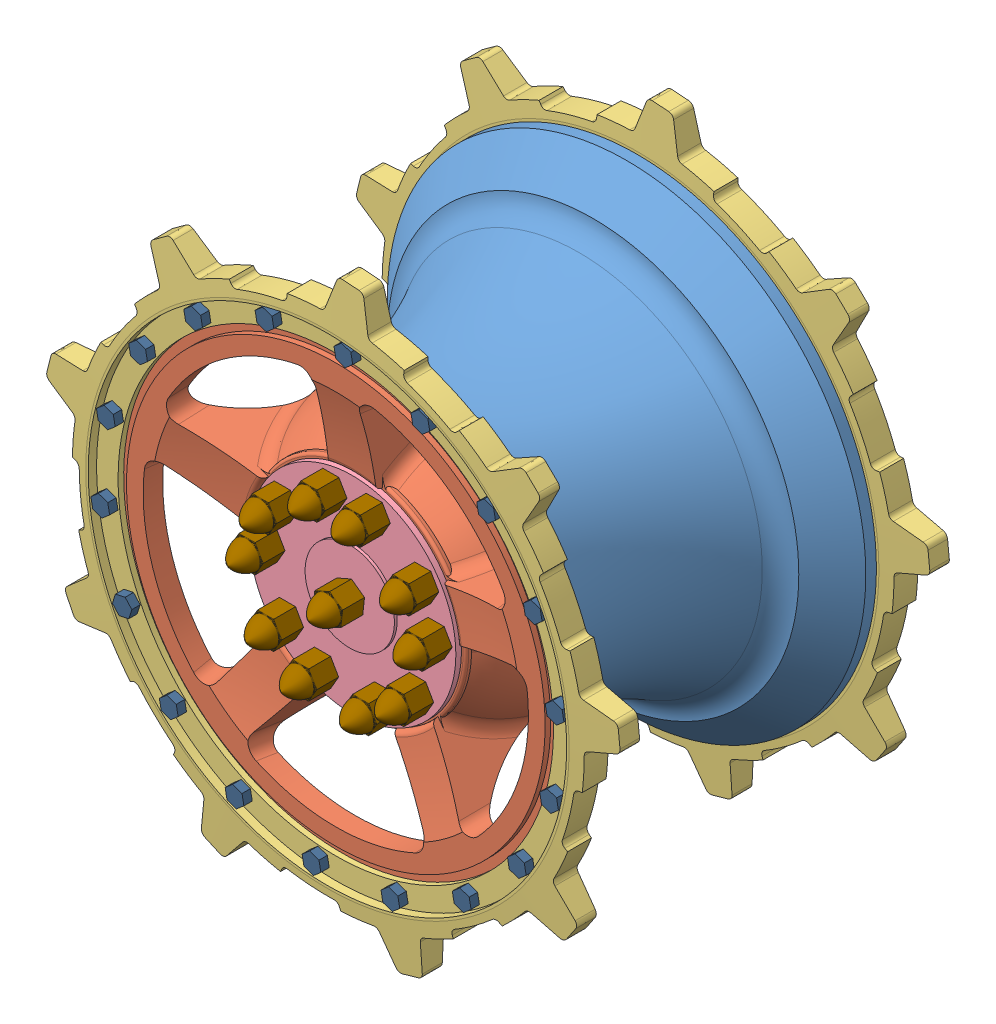
SolidWorks assembly Drive Wheel, configuration Default. Lengths in mm.
Overall size (36.71 36.7 16.14).
94 component instances, 10 part files, 114 mates.
Components (placement in the parent):
- Drive Wheel inner hub-1: Drive Wheel inner hub [Default] at (9.6783 0.3755 -10.4549) size (21.77 21.77 10.19)
- Drive Wheel outer hub-1: Drive Wheel outer hub [Default] at (9.6783 0.3755 3.5405) x (-0.809017 -0.587785 0) z (0 0 -1) size (21.77 21.77 4.19)
- Drive Wheel Sprocket-1: Drive Wheel Sprocket [Default] at (9.6783 0.3755 3.5913) x (0.997564 -0.069756 0) z (0 0 1) size (26.15 25.76 1.17)
- Drive Wheel Sprocket-2: Drive Wheel Sprocket [Default] at (9.6783 0.3755 -10.5057) x (-0.71934 0.694658 0) z (0 0 -1) size (26.15 25.76 1.17)
- Drive Wheel Bearing Plate-1: Drive Wheel Bearing Plate [Default] at (6.2039 -0.1061 2.7785) size (9.4 9.4 0.38)
- Drive Wheel Bearing Assembly-1: Drive Wheel Bearing Assembly [Default] at (10.4373 0.6578 -3.4809) x (1 0 0) z (0 1 0) size (5.14 1.27 5.06)
  - Drive Wheel Bearing-1: Drive Wheel Bearing [Default] at (-0.759 1.0051 -0.2823) size (4.83 1.27 4.83)
  - Drive Wheel Bearing Roller-1: Drive Wheel Bearing Roller [Default] at (-0.759 -0.1093 1.8348) x (-0.999426 -0.00354 0.033681) z (0 0.994522 0.104528) size (0.64 0.64 0.89)
  - Drive Wheel Bearing Roller-2: Drive Wheel Bearing Roller [Default] at (-2.6729 0.7749 -1.3873) x (0.789274 0.103648 0.60523) z (0.090524 -0.994522 0.052264) size (0.64 0.64 0.89)
  - Drive Wheel Bearing Roller-3: Drive Wheel Bearing Roller [Default] at (-0.759 0.7749 -2.4923) x (1 0 0) z (0 -0.994522 0.104528) size (0.64 0.64 0.89)
  - Drive Wheel Bearing Roller-4: Drive Wheel Bearing Roller [Default] at (-0.0031 0.7749 -2.3591) x (0.927484 0.003582 0.373846) z (-0.035751 -0.994522 0.098225) size (0.64 0.64 0.89)
  - Drive Wheel Bearing Roller-5: Drive Wheel Bearing Roller [Default] at (-2.1199 -0.1093 1.3395) x (0.99582 0.061868 0.06719) z (-0.06719 0.994522 0.080073) size (0.64 0.64 0.89)
  - Drive Wheel Bearing Roller-6: Drive Wheel Bearing Roller [Default] at (-2.8439 -0.1093 0.0853) x (0.979533 0.098182 0.175711) z (-0.10294 0.994522 0.018151) size (0.64 0.64 0.89)
  - Drive Wheel Bearing Roller-7: Drive Wheel Bearing Roller [Default] at (-2.1796 0.7749 -1.9753) x (0.99582 0.061868 -0.06719) z (0.06719 -0.994522 0.080073) size (0.64 0.64 0.89)
  - Drive Wheel Bearing Roller-8: Drive Wheel Bearing Roller [Default] at (-2.5925 -0.1093 0.7762) x (0.992212 0.085557 0.090524) z (-0.090524 0.994522 0.052264) size (0.64 0.64 0.89)
  - Drive Wheel Bearing Roller-9: Drive Wheel Bearing Roller [Default] at (-1.4831 -0.1093 1.7071) x (0.998836 0.032375 0.035751) z (-0.035751 0.994522 0.098225) size (0.64 0.64 0.89)
  - Drive Wheel Bearing Roller-10: Drive Wheel Bearing Roller [Default] at (-1.5149 0.7749 -2.3591) x (0.998836 0.032375 -0.035751) z (0.035751 -0.994522 0.098225) size (0.64 0.64 0.89)
  - Drive Wheel Bearing Roller-11: Drive Wheel Bearing Roller [Default] at (-2.9355 0.7749 -0.6661) x (0.986505 0.104412 0.126122) z (0.10294 -0.994522 0.018151) size (0.64 0.64 0.89)
  - Drive Wheel Bearing Roller-12: Drive Wheel Bearing Roller [Default] at (1.4174 0.7749 -0.6661) x (0.885883 -0.083366 0.456356) z (-0.10294 -0.994522 0.018151) size (0.64 0.64 0.89)
  - Drive Wheel Bearing Roller-13: Drive Wheel Bearing Roller [Default] at (1.0745 -0.1093 0.7762) x (0.992212 -0.085557 -0.090524) z (0.090524 0.994522 0.052264) size (0.64 0.64 0.89)
  - Drive Wheel Bearing Roller-14: Drive Wheel Bearing Roller [Default] at (0.6018 -0.1093 1.3395) x (0.874291 -0.097355 0.47554) z (0.06719 0.994522 0.080073) size (0.64 0.64 0.89)
  - Drive Wheel Bearing Roller-15: Drive Wheel Bearing Roller [Default] at (0.6616 0.7749 -1.9753) x (0.913673 -0.093574 -0.395532) z (-0.06719 -0.994522 0.080073) size (0.64 0.64 0.89)
  - Drive Wheel Bearing Roller-16: Drive Wheel Bearing Roller [Default] at (1.1549 0.7749 -1.3873) x (0.899555 -0.059136 0.432785) z (-0.090524 -0.994522 0.052264) size (0.64 0.64 0.89)
  - Drive Wheel Bearing Roller-17: Drive Wheel Bearing Roller [Default] at (1.3259 -0.1093 0.0853) x (0.989592 -0.100551 -0.10294) z (0.10294 0.994522 0.018151) size (0.64 0.64 0.89)
  - Drive Wheel Bearing Roller-18: Drive Wheel Bearing Roller [Default] at (-0.0349 -0.1093 1.7071) x (0.70634 -0.094677 0.701512) z (0.035751 0.994522 0.098225) size (0.64 0.64 0.89)
- Drive Wheel Bearing Assembly-2: Drive Wheel Bearing Assembly [Default] at (9.7005 -0.434 0.5034) x (0.374215 -0.927342 0) z (-0.927342 -0.374215 0) size (5.14 1.27 5.06)
  - Drive Wheel Bearing-1: Drive Wheel Bearing [Default] at (-0.759 1.0051 -0.2823) size (4.83 1.27 4.83)
  - Drive Wheel Bearing Roller-1: Drive Wheel Bearing Roller [Default] at (-0.759 -0.1093 1.8348) x (-0.999426 -0.00354 0.033681) z (0 0.994522 0.104528) size (0.64 0.64 0.89)
  - Drive Wheel Bearing Roller-2: Drive Wheel Bearing Roller [Default] at (-2.6729 0.7749 -1.3873) x (0.789274 0.103648 0.60523) z (0.090524 -0.994522 0.052264) size (0.64 0.64 0.89)
  - Drive Wheel Bearing Roller-3: Drive Wheel Bearing Roller [Default] at (-0.759 0.7749 -2.4923) x (1 0 0) z (0 -0.994522 0.104528) size (0.64 0.64 0.89)
  - Drive Wheel Bearing Roller-4: Drive Wheel Bearing Roller [Default] at (-0.0031 0.7749 -2.3591) x (0.927484 0.003582 0.373846) z (-0.035751 -0.994522 0.098225) size (0.64 0.64 0.89)
  - Drive Wheel Bearing Roller-5: Drive Wheel Bearing Roller [Default] at (-2.1199 -0.1093 1.3395) x (0.99582 0.061868 0.06719) z (-0.06719 0.994522 0.080073) size (0.64 0.64 0.89)
  - Drive Wheel Bearing Roller-6: Drive Wheel Bearing Roller [Default] at (-2.8439 -0.1093 0.0853) x (0.979533 0.098182 0.175711) z (-0.10294 0.994522 0.018151) size (0.64 0.64 0.89)
  - Drive Wheel Bearing Roller-7: Drive Wheel Bearing Roller [Default] at (-2.1796 0.7749 -1.9753) x (0.99582 0.061868 -0.06719) z (0.06719 -0.994522 0.080073) size (0.64 0.64 0.89)
  - Drive Wheel Bearing Roller-8: Drive Wheel Bearing Roller [Default] at (-2.5925 -0.1093 0.7762) x (0.992212 0.085557 0.090524) z (-0.090524 0.994522 0.052264) size (0.64 0.64 0.89)
  - Drive Wheel Bearing Roller-9: Drive Wheel Bearing Roller [Default] at (-1.4831 -0.1093 1.7071) x (0.998836 0.032375 0.035751) z (-0.035751 0.994522 0.098225) size (0.64 0.64 0.89)
  - Drive Wheel Bearing Roller-10: Drive Wheel Bearing Roller [Default] at (-1.5149 0.7749 -2.3591) x (0.998836 0.032375 -0.035751) z (0.035751 -0.994522 0.098225) size (0.64 0.64 0.89)
  - Drive Wheel Bearing Roller-11: Drive Wheel Bearing Roller [Default] at (-2.9355 0.7749 -0.6661) x (0.986505 0.104412 0.126122) z (0.10294 -0.994522 0.018151) size (0.64 0.64 0.89)
  - Drive Wheel Bearing Roller-12: Drive Wheel Bearing Roller [Default] at (1.4174 0.7749 -0.6661) x (0.885883 -0.083366 0.456356) z (-0.10294 -0.994522 0.018151) size (0.64 0.64 0.89)
  - Drive Wheel Bearing Roller-13: Drive Wheel Bearing Roller [Default] at (1.0745 -0.1093 0.7762) x (0.992212 -0.085557 -0.090524) z (0.090524 0.994522 0.052264) size (0.64 0.64 0.89)
  - Drive Wheel Bearing Roller-14: Drive Wheel Bearing Roller [Default] at (0.6018 -0.1093 1.3395) x (0.874291 -0.097355 0.47554) z (0.06719 0.994522 0.080073) size (0.64 0.64 0.89)
  - Drive Wheel Bearing Roller-15: Drive Wheel Bearing Roller [Default] at (0.6616 0.7749 -1.9753) x (0.913673 -0.093574 -0.395532) z (-0.06719 -0.994522 0.080073) size (0.64 0.64 0.89)
  - Drive Wheel Bearing Roller-16: Drive Wheel Bearing Roller [Default] at (1.1549 0.7749 -1.3873) x (0.899555 -0.059136 0.432785) z (-0.090524 -0.994522 0.052264) size (0.64 0.64 0.89)
  - Drive Wheel Bearing Roller-17: Drive Wheel Bearing Roller [Default] at (1.3259 -0.1093 0.0853) x (0.989592 -0.100551 -0.10294) z (0.10294 0.994522 0.018151) size (0.64 0.64 0.89)
  - Drive Wheel Bearing Roller-18: Drive Wheel Bearing Roller [Default] at (-0.0349 -0.1093 1.7071) x (0.70634 -0.094677 0.701512) z (0.035751 0.994522 0.098225) size (0.64 0.64 0.89)
- Bearing Washer-1: Bearing Washer [Default] at (29.8938 -4.5317 1.7625) x (1 0 0) z (0 1 0) size (5.51 0.25 5.51)
- Bearing nut-1: Bearing nut [Default] at (9.6783 0.3755 2.5245) x (1 0 0) z (0 1 0) size (4.94 0.76 4.6)
- Drive Wheel Nut-1: Drive Wheel Nut [Default] at (11.0437 -3.1814 3.0325) size (1.47 1.31 7.99)
- Drive Wheel Nut-2: Drive Wheel Nut [Default] at (12.6392 -2.0222 3.0325) size (1.47 1.31 7.99)
- Drive Wheel Nut-3: Drive Wheel Nut [Default] at (13.4831 0.5749 3.0325) size (1.47 1.31 7.99)
- Drive Wheel Nut-4: Drive Wheel Nut [Default] at (12.8736 2.4506 3.0325) size (1.47 1.31 7.99)
- Drive Wheel Nut-5: Drive Wheel Nut [Default] at (6.7174 -2.0222 3.0325) size (1.47 1.31 7.99)
- Drive Wheel Nut-6: Drive Wheel Nut [Default] at (6.4829 2.4506 3.0325) size (1.47 1.31 7.99)
- Drive Wheel Nut-7: Drive Wheel Nut [Default] at (5.8735 0.5749 3.0325) size (1.47 1.31 7.99)
- Drive Wheel Nut-8: Drive Wheel Nut [Default] at (8.6922 4.0557 3.0325) size (1.47 1.31 7.99)
- Drive Wheel Nut-9: Drive Wheel Nut [Default] at (9.6783 0.3755 3.1595) x (0.107676 0.994186 0) z (0 0 1) size (1.47 1.31 7.99)
- Drive Wheel Nut-10: Drive Wheel Nut [Default] at (8.3129 -3.1814 3.0325) size (1.47 1.31 7.99)
- Drive Wheel Nut-11: Drive Wheel Nut [Default] at (10.6644 4.0557 3.0325) size (1.47 1.31 7.99)
- Sprocket bolt-1: Sprocket bolt [Default] at (10.4034 10.7452 3.1595) x (0.922387 0.386268 0) z (0.386268 -0.922387 0) size (0.86 1.02 0.88)
- Sprocket bolt-2: Sprocket bolt [Default] at (13.9063 9.8718 3.1595) x (0.922387 0.386268 0) z (0.386268 -0.922387 0) size (0.86 1.02 0.88)
- Sprocket bolt-3: Sprocket bolt [Default] at (16.8992 7.853 3.1595) x (0.922387 0.386268 0) z (0.386268 -0.922387 0) size (0.86 1.02 0.88)
- Sprocket bolt-4: Sprocket bolt [Default] at (19.0212 4.9324 3.1595) x (0.922387 0.386268 0) z (0.386268 -0.922387 0) size (0.86 1.02 0.88)
- Sprocket bolt-5: Sprocket bolt [Default] at (20.0163 1.4621 3.1595) x (0.922387 0.386268 0) z (0.386268 -0.922387 0) size (0.86 1.02 0.88)
- Sprocket bolt-6: Sprocket bolt [Default] at (19.7645 -2.1392 3.1595) x (0.922387 0.386268 0) z (0.386268 -0.922387 0) size (0.86 1.02 0.88)
- Sprocket bolt-7: Sprocket bolt [Default] at (18.2961 -5.4373 3.1595) x (0.922387 0.386268 0) z (0.386268 -0.922387 0) size (0.86 1.02 0.88)
- Sprocket bolt-8: Sprocket bolt [Default] at (15.7883 -8.0342 3.1595) x (0.922387 0.386268 0) z (0.386268 -0.922387 0) size (0.86 1.02 0.88)
- Sprocket bolt-9: Sprocket bolt [Default] at (12.5435 -9.6167 3.1595) x (0.922387 0.386268 0) z (0.386268 -0.922387 0) size (0.86 1.02 0.88)
- Sprocket bolt-10: Sprocket bolt [Default] at (8.9532 -9.9941 3.1595) x (0.922387 0.386268 0) z (0.386268 -0.922387 0) size (0.86 1.02 0.88)
- Sprocket bolt-11: Sprocket bolt [Default] at (5.4503 -9.1207 3.1595) x (0.922387 0.386268 0) z (0.386268 -0.922387 0) size (0.86 1.02 0.88)
- Sprocket bolt-12: Sprocket bolt [Default] at (2.4573 -7.102 3.1595) x (0.922387 0.386268 0) z (0.386268 -0.922387 0) size (0.86 1.02 0.88)
- Sprocket bolt-13: Sprocket bolt [Default] at (0.3354 -4.1813 3.1595) x (0.994954 -0.100336 0) z (-0.100336 -0.994954 0) size (0.86 1.02 0.88)
- Sprocket bolt-14: Sprocket bolt [Default] at (-0.6597 -0.711 3.1595) x (0.922387 0.386268 0) z (0.386268 -0.922387 0) size (0.86 1.02 0.88)
- Sprocket bolt-15: Sprocket bolt [Default] at (-0.4079 2.8903 3.1595) x (0.922387 0.386268 0) z (0.386268 -0.922387 0) size (0.86 1.02 0.88)
- Sprocket bolt-16: Sprocket bolt [Default] at (1.0605 6.1883 3.1595) x (0.922387 0.386268 0) z (0.386268 -0.922387 0) size (0.86 1.02 0.88)
- Sprocket bolt-17: Sprocket bolt [Default] at (3.5683 8.7852 3.1595) x (0.922387 0.386268 0) z (0.386268 -0.922387 0) size (0.86 1.02 0.88)
- Sprocket bolt-18: Sprocket bolt [Default] at (6.813 10.3678 3.1595) x (0.922387 0.386268 0) z (0.386268 -0.922387 0) size (0.86 1.02 0.88)
- Sprocket bolt-19: Sprocket bolt [Default] at (16.8992 7.853 -10.0739) x (0.782051 -0.623214 0) z (0.623214 0.782051 0) size (0.86 1.02 0.88)
- Sprocket bolt-20: Sprocket bolt [Default] at (13.9063 9.8718 -10.0739) x (0.998647 -0.052005 0) z (0.052005 0.998647 0) size (0.86 1.02 0.88)
- Sprocket bolt-21: Sprocket bolt [Default] at (10.4034 10.7452 -10.0739) x (0.998647 -0.052005 0) z (0.052005 0.998647 0) size (0.86 1.02 0.88)
- Sprocket bolt-22: Sprocket bolt [Default] at (6.813 10.3678 -10.0739) x (0.998647 -0.052005 0) z (0.052005 0.998647 0) size (0.86 1.02 0.88)
- Sprocket bolt-23: Sprocket bolt [Default] at (3.5683 8.7852 -10.0739) x (0.998647 -0.052005 0) z (0.052005 0.998647 0) size (0.86 1.02 0.88)
- Sprocket bolt-24: Sprocket bolt [Default] at (1.0605 6.1883 -10.0739) x (0.998647 -0.052005 0) z (0.052005 0.998647 0) size (0.86 1.02 0.88)
- Sprocket bolt-25: Sprocket bolt [Default] at (-0.4079 2.8903 -10.0739) x (0.998647 -0.052005 0) z (0.052005 0.998647 0) size (0.86 1.02 0.88)
- Sprocket bolt-26: Sprocket bolt [Default] at (-0.6597 -0.711 -10.0739) x (0.998647 -0.052005 0) z (0.052005 0.998647 0) size (0.86 1.02 0.88)
- Sprocket bolt-27: Sprocket bolt [Default] at (0.3354 -4.1813 -10.0739) x (0.998647 -0.052005 0) z (0.052005 0.998647 0) size (0.86 1.02 0.88)
- Sprocket bolt-28: Sprocket bolt [Default] at (2.4573 -7.102 -10.0739) x (0.998647 -0.052005 0) z (0.052005 0.998647 0) size (0.86 1.02 0.88)
- Sprocket bolt-29: Sprocket bolt [Default] at (5.4503 -9.1207 -10.0739) x (0.998647 -0.052005 0) z (0.052005 0.998647 0) size (0.86 1.02 0.88)
- Sprocket bolt-30: Sprocket bolt [Default] at (8.9532 -9.9941 -10.0739) x (0.998647 -0.052005 0) z (0.052005 0.998647 0) size (0.86 1.02 0.88)
- Sprocket bolt-31: Sprocket bolt [Default] at (12.5435 -9.6167 -10.0739) x (0.998647 -0.052005 0) z (0.052005 0.998647 0) size (0.86 1.02 0.88)
- Sprocket bolt-32: Sprocket bolt [Default] at (15.7883 -8.0342 -10.0739) x (0.998647 -0.052005 0) z (0.052005 0.998647 0) size (0.86 1.02 0.88)
- Sprocket bolt-33: Sprocket bolt [Default] at (18.2961 -5.4373 -10.0739) x (0.998647 -0.052005 0) z (0.052005 0.998647 0) size (0.86 1.02 0.88)
- Sprocket bolt-34: Sprocket bolt [Default] at (19.7645 -2.1392 -10.0739) x (0.998647 -0.052005 0) z (0.052005 0.998647 0) size (0.86 1.02 0.88)
- Sprocket bolt-35: Sprocket bolt [Default] at (20.0163 1.4621 -10.0739) x (0.998647 -0.052005 0) z (0.052005 0.998647 0) size (0.86 1.02 0.88)
- Sprocket bolt-36: Sprocket bolt [Default] at (19.0212 4.9324 -10.0739) x (0.998647 -0.052005 0) z (0.052005 0.998647 0) size (0.86 1.02 0.88)
Mates (geometry in assembly coordinates):
- Coincident1: coincident anti-aligned: plane of Drive Wheel inner hub-1 through (16.0384 0.3755 -0.2695) normal (0 0 1); plane of Drive Wheel outer hub-1 through (9.6783 0.3755 -0.2695) normal (0 0 -1)
- Concentric1: concentric aligned: cone of Drive Wheel inner hub-1 through (9.6783 0.3755 -4.4859) axis (0 0 1); cylinder of Drive Wheel outer hub-1 through (9.6783 0.3755 1.5085) axis (0 0 1) radius 3.0208
- Concentric2: concentric anti-aligned: cylinder of Drive Wheel inner hub-1 through (10.6644 4.0557 2.1181) axis (0 0 -1) radius 0.4445; cylinder of Drive Wheel outer hub-1 through (10.6644 4.0557 -0.3521) axis (0 0 1) radius 0.4445
- Coincident2: coincident anti-aligned: plane of Drive Wheel outer hub-1 through (9.6783 0.3755 3.5405) normal (0 0 1); plane of Drive Wheel Sprocket-1 through (9.6783 0.3755 3.5405) normal (0 0 -1)
- Concentric3: concentric anti-aligned: cylinder of Drive Wheel outer hub-1 through (9.6783 0.3755 2.9055) axis (0 0 1) radius 10.8839; cylinder of Drive Wheel Sprocket-1 through (9.6783 0.3755 4.1755) axis (0 0 -1) radius 10.8839
- Concentric4: concentric aligned: cylinder of Drive Wheel outer hub-1 through (10.4034 10.7452 3.1595) axis (0 0 1) radius 0.254; cylinder of Drive Wheel Sprocket-1 through (10.4034 10.7452 3.5405) axis (0 0 1) radius 0.254
- Coincident3: coincident anti-aligned: plane of Drive Wheel inner hub-1 through (9.6783 0.3755 -10.4549) normal (0 0 -1); plane of Drive Wheel Sprocket-2 through (9.6783 0.3755 -10.4549) normal (0 0 1)
- Concentric5: concentric anti-aligned: cylinder of Drive Wheel inner hub-1 through (9.6783 0.3755 -9.4389) axis (0 0 -1) radius 10.8839; cylinder of Drive Wheel Sprocket-2 through (9.6783 0.3755 -11.0899) axis (0 0 1) radius 10.8839
- Concentric6: concentric aligned: cylinder of Drive Wheel inner hub-1 through (10.4034 10.7452 -10.0739) axis (0 0 -1) radius 0.254; cylinder of Drive Wheel Sprocket-2 through (10.4034 10.7452 -10.4549) axis (0 0 -1) radius 0.254
- Concentric7: concentric aligned: cylinder of Drive Wheel outer hub-1 through (9.6783 0.3755 1.5085) axis (0 0 1) radius 3.0208; cylinder of Drive Wheel Bearing Assembly-2/Drive Wheel Bearing-1 through (9.6783 0.3755 0.2385) axis (0 0 1) radius 1.524
- Coincident4: coincident aligned: plane of Drive Wheel outer hub-1 through (9.6783 0.3755 1.5085) normal (0 0 1); plane of Drive Wheel Bearing Assembly-2/Drive Wheel Bearing-1 through (9.6783 0.3755 1.5085) normal (0 0 1)
- Coincident5: coincident anti-aligned: plane of Drive Wheel outer hub-1 through (9.6783 0.3755 1.5085) normal (0 0 1); plane of Bearing Washer-1 through (9.6783 0.3755 1.5085) normal (0 0 -1)
- Concentric8: concentric aligned: cylinder of Drive Wheel outer hub-1 through (9.6783 0.3755 1.5085) axis (0 0 1) radius 3.0208; cylinder of Bearing Washer-1 through (9.6783 0.3755 1.5085) axis (0 0 1) radius 1.524
- Coincident6: coincident anti-aligned: plane of Bearing Washer-1 through (9.6783 0.3755 1.7625) normal (0 0 1); plane of Bearing nut-1 through (13.1094 -2.246 1.7625) normal (0 0 -1)
- Concentric9: concentric aligned: cylinder of Bearing Washer-1 through (9.6783 0.3755 1.5085) axis (0 0 1) radius 1.524; cylinder of Bearing nut-1 through (9.6783 0.3755 1.7625) axis (0 0 1) radius 1.524
- Coincident7: coincident anti-aligned: plane of Drive Wheel outer hub-1 through (9.6783 0.3755 2.7785) normal (0 0 1); plane of Drive Wheel Bearing Plate-1 through (9.6783 0.3755 2.7785) normal (0 0 -1)
- Concentric10: concentric aligned: cylinder of Drive Wheel Bearing Plate-1 through (9.6783 0.3755 1.5212) axis (0 0 1) radius 0.4445; cylinder of Bearing nut-1 through (9.6783 0.3755 1.7625) axis (0 0 1) radius 1.524
- Concentric11: concentric aligned: cylinder of Drive Wheel outer hub-1 through (8.6922 4.0557 -0.3521) axis (0 0 1) radius 0.4445; cylinder of Drive Wheel Bearing Plate-1 through (8.6922 4.0557 1.5212) axis (0 0 1) radius 0.4445
- Coincident8: coincident aligned: plane of Drive Wheel Nut-8 through (8.6922 4.0557 -3.0635) normal (0 0 -1); plane of Drive Wheel Nut-11 through (10.6644 4.0557 -3.0635) normal (0 0 -1)
- Coincident9: coincident aligned: plane of Drive Wheel Nut-4 through (12.8736 2.4506 -3.0635) normal (0 0 -1); plane of Drive Wheel Nut-11 through (10.6644 4.0557 -3.0635) normal (0 0 -1)
- Coincident10: coincident aligned: plane of Drive Wheel Nut-3 through (13.4831 0.5749 -3.0635) normal (0 0 -1); plane of Drive Wheel Nut-4 through (12.8736 2.4506 -3.0635) normal (0 0 -1)
- Coincident11: coincident aligned: plane of Drive Wheel Nut-2 through (12.6392 -2.0222 -3.0635) normal (0 0 -1); plane of Drive Wheel Nut-3 through (13.4831 0.5749 -3.0635) normal (0 0 -1)
- Coincident12: coincident aligned: plane of Drive Wheel Nut-1 through (11.0437 -3.1814 -3.0635) normal (0 0 -1); plane of Drive Wheel Nut-2 through (12.6392 -2.0222 -3.0635) normal (0 0 -1)
- Coincident13: coincident aligned: plane of Drive Wheel Nut-1 through (11.0437 -3.1814 -3.0635) normal (0 0 -1); plane of Drive Wheel Nut-10 through (8.3129 -3.1814 -3.0635) normal (0 0 -1)
- Coincident14: coincident aligned: plane of Drive Wheel Nut-5 through (6.7174 -2.0222 -3.0635) normal (0 0 -1); plane of Drive Wheel Nut-10 through (8.3129 -3.1814 -3.0635) normal (0 0 -1)
- Coincident15: coincident aligned: plane of Drive Wheel Nut-5 through (6.7174 -2.0222 -3.0635) normal (0 0 -1); plane of Drive Wheel Nut-7 through (5.8735 0.5749 -3.0635) normal (0 0 -1)
- Coincident16: coincident aligned: plane of Drive Wheel Nut-6 through (6.4829 2.4506 -3.0635) normal (0 0 -1); plane of Drive Wheel Nut-7 through (5.8735 0.5749 -3.0635) normal (0 0 -1)
- Coincident18: coincident anti-aligned: plane of Drive Wheel Bearing Plate-1 through (9.6783 0.3755 3.0325) normal (0 0 1); plane of Drive Wheel Nut-8 through (9.792 4.6907 3.0325) normal (0 0 -1)
- Concentric12: concentric aligned: cylinder of Drive Wheel Bearing Plate-1 through (8.6922 4.0557 1.5212) axis (0 0 1) radius 0.4445; cylinder of Drive Wheel Nut-8 through (8.6922 4.0557 -3.0635) axis (0 0 1) radius 0.4445
- Coincident19: coincident aligned: circle of Drive Wheel Bearing Plate-1; cylinder of Drive Wheel Nut-11 through (10.6644 4.0557 -3.0635) axis (0 0 1) radius 0.4445
- Coincident20: coincident anti-aligned: circle of Drive Wheel Bearing Plate-1; cylinder of Drive Wheel Nut-4 through (12.8736 2.4506 -3.0635) axis (0 0 1) radius 0.4445
- Coincident21: coincident aligned: circle of Drive Wheel Bearing Plate-1; cylinder of Drive Wheel Nut-3 through (13.4831 0.5749 -3.0635) axis (0 0 1) radius 0.4445
- Coincident22: coincident aligned: circle of Drive Wheel Bearing Plate-1; cylinder of Drive Wheel Nut-2 through (12.6392 -2.0222 -3.0635) axis (0 0 1) radius 0.4445
- Coincident23: coincident aligned: circle of Drive Wheel Bearing Plate-1; cylinder of Drive Wheel Nut-1 through (11.0437 -3.1814 -3.0635) axis (0 0 1) radius 0.4445
- Concentric13: concentric aligned: cylinder of Drive Wheel Nut-10 through (8.3129 -3.1814 -3.0635) axis (0 0 1) radius 0.4445; cylinder of Drive Wheel outer hub-1 through (8.3129 -3.1814 -0.3521) axis (0 0 1) radius 0.4445
- Concentric14: concentric aligned: cylinder of Drive Wheel outer hub-1 through (6.7174 -2.0222 -0.3521) axis (0 0 1) radius 0.4445; cylinder of Drive Wheel Nut-5 through (6.7174 -2.0222 -3.0635) axis (0 0 1) radius 0.4445
- Concentric15: concentric aligned: cylinder of Drive Wheel outer hub-1 through (5.8735 0.5749 -0.3521) axis (0 0 1) radius 0.4445; cylinder of Drive Wheel Nut-7 through (5.8735 0.5749 -3.0635) axis (0 0 1) radius 0.4445
- Concentric16: concentric aligned: cylinder of Drive Wheel outer hub-1 through (6.4829 2.4506 -0.3521) axis (0 0 1) radius 0.4445; cylinder of Drive Wheel Nut-6 through (6.4829 2.4506 -3.0635) axis (0 0 1) radius 0.4445
- Concentric17: concentric aligned: cylinder of Drive Wheel Bearing Plate-1 through (9.6783 0.3755 1.5212) axis (0 0 1) radius 0.4445; cylinder of Drive Wheel Nut-9 through (9.6783 0.3755 -2.9365) axis (0 0 1) radius 0.4445
- Coincident24: coincident anti-aligned: plane of Drive Wheel Bearing Plate-1 through (9.6783 0.3755 3.1595) normal (0 0 1); plane of Drive Wheel Nut-9 through (9.1654 1.5374 3.1595) normal (0 0 -1)
- Coincident25: coincident aligned: plane of Sprocket bolt-1 through (10.8299 10.5962 4.1755) normal (0 0 1); plane of Sprocket bolt-2 through (14.3328 9.7229 4.1755) normal (0 0 1)
- Coincident26: coincident aligned: plane of Sprocket bolt-2 through (14.3328 9.7229 4.1755) normal (0 0 1); plane of Sprocket bolt-3 through (17.3257 7.7041 4.1755) normal (0 0 1)
- Coincident27: coincident aligned: plane of Sprocket bolt-3 through (17.3257 7.7041 4.1755) normal (0 0 1); plane of Sprocket bolt-4 through (19.4477 4.7835 4.1755) normal (0 0 1)
- Coincident28: coincident aligned: plane of Sprocket bolt-4 through (19.4477 4.7835 4.1755) normal (0 0 1); plane of Sprocket bolt-5 through (20.4428 1.3132 4.1755) normal (0 0 1)
- Coincident29: coincident aligned: plane of Sprocket bolt-5 through (20.4428 1.3132 4.1755) normal (0 0 1); plane of Sprocket bolt-6 through (20.1909 -2.2882 4.1755) normal (0 0 1)
- Coincident30: coincident aligned: plane of Sprocket bolt-7 through (18.7226 -5.5862 4.1755) normal (0 0 1); plane of Sprocket bolt-8 through (16.2147 -8.1831 4.1755) normal (0 0 1)
- Coincident31: coincident aligned: plane of Sprocket bolt-8 through (16.2147 -8.1831 4.1755) normal (0 0 1); plane of Sprocket bolt-9 through (12.97 -9.7657 4.1755) normal (0 0 1)
- Coincident32: coincident aligned: plane of Sprocket bolt-9 through (12.97 -9.7657 4.1755) normal (0 0 1); plane of Sprocket bolt-10 through (9.3796 -10.143 4.1755) normal (0 0 1)
- Coincident33: coincident aligned: plane of Sprocket bolt-10 through (9.3796 -10.143 4.1755) normal (0 0 1); plane of Sprocket bolt-11 through (5.8767 -9.2696 4.1755) normal (0 0 1)
- Coincident34: coincident aligned: plane of Sprocket bolt-11 through (5.8767 -9.2696 4.1755) normal (0 0 1); plane of Sprocket bolt-12 through (2.8838 -7.2509 4.1755) normal (0 0 1)
- Coincident35: coincident aligned: plane of Sprocket bolt-6 through (20.1909 -2.2882 4.1755) normal (0 0 1); plane of Sprocket bolt-7 through (18.7226 -5.5862 4.1755) normal (0 0 1)
- Coincident36: coincident aligned: plane of Sprocket bolt-13 through (0.6392 -4.5156 4.1755) normal (0 0 1); plane of Sprocket bolt-14 through (-0.2333 -0.86 4.1755) normal (0 0 1)
- Coincident37: coincident aligned: plane of Sprocket bolt-14 through (-0.2333 -0.86 4.1755) normal (0 0 1); plane of Sprocket bolt-15 through (0.0186 2.7414 4.1755) normal (0 0 1)
- Coincident38: coincident aligned: plane of Sprocket bolt-15 through (0.0186 2.7414 4.1755) normal (0 0 1); plane of Sprocket bolt-16 through (1.4869 6.0394 4.1755) normal (0 0 1)
- Coincident39: coincident aligned: plane of Sprocket bolt-16 through (1.4869 6.0394 4.1755) normal (0 0 1); plane of Sprocket bolt-17 through (3.9948 8.6363 4.1755) normal (0 0 1)
- Coincident40: coincident aligned: plane of Sprocket bolt-17 through (3.9948 8.6363 4.1755) normal (0 0 1); plane of Sprocket bolt-18 through (7.2395 10.2189 4.1755) normal (0 0 1)
- Coincident41: coincident aligned: plane of Sprocket bolt-12 through (2.8838 -7.2509 4.1755) normal (0 0 1); plane of Sprocket bolt-13 through (0.6392 -4.5156 4.1755) normal (0 0 1)
- Coincident42: coincident aligned: plane of Sprocket bolt-19 through (17.3501 7.88 -11.0899) normal (0 0 -1); plane of Sprocket bolt-20 through (14.2574 10.156 -11.0899) normal (0 0 -1)
- Coincident43: coincident aligned: plane of Sprocket bolt-20 through (14.2574 10.156 -11.0899) normal (0 0 -1); plane of Sprocket bolt-21 through (10.7545 11.0294 -11.0899) normal (0 0 -1)
- Coincident44: coincident aligned: plane of Sprocket bolt-21 through (10.7545 11.0294 -11.0899) normal (0 0 -1); plane of Sprocket bolt-22 through (7.1641 10.652 -11.0899) normal (0 0 -1)
- Coincident45: coincident aligned: plane of Sprocket bolt-22 through (7.1641 10.652 -11.0899) normal (0 0 -1); plane of Sprocket bolt-23 through (3.9194 9.0694 -11.0899) normal (0 0 -1)
- Coincident46: coincident aligned: plane of Sprocket bolt-23 through (3.9194 9.0694 -11.0899) normal (0 0 -1); plane of Sprocket bolt-24 through (1.4116 6.4725 -11.0899) normal (0 0 -1)
- Coincident47: coincident aligned: plane of Sprocket bolt-24 through (1.4116 6.4725 -11.0899) normal (0 0 -1); plane of Sprocket bolt-25 through (-0.0568 3.1745 -11.0899) normal (0 0 -1)
- Coincident48: coincident aligned: plane of Sprocket bolt-25 through (-0.0568 3.1745 -11.0899) normal (0 0 -1); plane of Sprocket bolt-26 through (-0.3086 -0.4268 -11.0899) normal (0 0 -1)
- Coincident49: coincident aligned: plane of Sprocket bolt-26 through (-0.3086 -0.4268 -11.0899) normal (0 0 -1); plane of Sprocket bolt-27 through (0.6865 -3.8971 -11.0899) normal (0 0 -1)
- Coincident50: coincident aligned: plane of Sprocket bolt-27 through (0.6865 -3.8971 -11.0899) normal (0 0 -1); plane of Sprocket bolt-28 through (2.8084 -6.8178 -11.0899) normal (0 0 -1)
- Coincident51: coincident aligned: plane of Sprocket bolt-28 through (2.8084 -6.8178 -11.0899) normal (0 0 -1); plane of Sprocket bolt-29 through (5.8014 -8.8365 -11.0899) normal (0 0 -1)
- Coincident52: coincident aligned: plane of Sprocket bolt-29 through (5.8014 -8.8365 -11.0899) normal (0 0 -1); plane of Sprocket bolt-30 through (9.3043 -9.7099 -11.0899) normal (0 0 -1)
- Coincident53: coincident aligned: plane of Sprocket bolt-31 through (12.8946 -9.3325 -11.0899) normal (0 0 -1); plane of Sprocket bolt-32 through (16.1394 -7.7499 -11.0899) normal (0 0 -1)
- Coincident54: coincident aligned: plane of Sprocket bolt-32 through (16.1394 -7.7499 -11.0899) normal (0 0 -1); plane of Sprocket bolt-33 through (18.6472 -5.153 -11.0899) normal (0 0 -1)
- Coincident55: coincident aligned: plane of Sprocket bolt-33 through (18.6472 -5.153 -11.0899) normal (0 0 -1); plane of Sprocket bolt-34 through (20.1156 -1.855 -11.0899) normal (0 0 -1)
- Coincident56: coincident aligned: plane of Sprocket bolt-34 through (20.1156 -1.855 -11.0899) normal (0 0 -1); plane of Sprocket bolt-35 through (20.3674 1.7463 -11.0899) normal (0 0 -1)
- Coincident57: coincident aligned: plane of Sprocket bolt-35 through (20.3674 1.7463 -11.0899) normal (0 0 -1); plane of Sprocket bolt-36 through (19.3723 5.2166 -11.0899) normal (0 0 -1)
- Coincident58: coincident aligned: plane of Sprocket bolt-30 through (9.3043 -9.7099 -11.0899) normal (0 0 -1); plane of Sprocket bolt-31 through (12.8946 -9.3325 -11.0899) normal (0 0 -1)
- Coincident59: coincident anti-aligned: plane of Drive Wheel Sprocket-2 through (9.6783 0.3755 -10.7089) normal (0 0 -1); plane of Sprocket bolt-24 through (1.4116 6.4725 -10.7089) normal (0 0 1)
- Coincident60: coincident anti-aligned: plane of Drive Wheel Sprocket-1 through (9.6783 0.3755 3.7945) normal (0 0 1); plane of Sprocket bolt-18 through (7.2395 10.2189 3.7945) normal (0 0 -1)
- Coincident61: coincident anti-aligned: circle of Drive Wheel outer hub-1; cylinder of Sprocket bolt-1 through (10.4034 10.7452 3.7945) axis (0 0 -1) radius 0.254
- Concentric18: concentric anti-aligned: cylinder of Drive Wheel Sprocket-1 through (13.9063 9.8718 3.5405) axis (0 0 1) radius 0.254; cylinder of Sprocket bolt-2 through (13.9063 9.8718 3.7945) axis (0 0 -1) radius 0.254
- Concentric19: concentric anti-aligned: cylinder of Drive Wheel Sprocket-1 through (16.8992 7.853 3.5405) axis (0 0 1) radius 0.254; cylinder of Sprocket bolt-3 through (16.8992 7.853 3.7945) axis (0 0 -1) radius 0.254
- Concentric20: concentric anti-aligned: cylinder of Drive Wheel Sprocket-1 through (19.0212 4.9324 3.5405) axis (0 0 1) radius 0.254; cylinder of Sprocket bolt-4 through (19.0212 4.9324 3.7945) axis (0 0 -1) radius 0.254
- Concentric21: concentric anti-aligned: cylinder of Drive Wheel Sprocket-1 through (20.0163 1.4621 3.5405) axis (0 0 1) radius 0.254; cylinder of Sprocket bolt-5 through (20.0163 1.4621 3.7945) axis (0 0 -1) radius 0.254
- Concentric22: concentric anti-aligned: cylinder of Drive Wheel Sprocket-1 through (19.7645 -2.1392 3.5405) axis (0 0 1) radius 0.254; cylinder of Sprocket bolt-6 through (19.7645 -2.1392 3.7945) axis (0 0 -1) radius 0.254
- Concentric23: concentric anti-aligned: cylinder of Drive Wheel Sprocket-1 through (18.2961 -5.4373 3.5405) axis (0 0 1) radius 0.254; cylinder of Sprocket bolt-7 through (18.2961 -5.4373 3.7945) axis (0 0 -1) radius 0.254
- Concentric24: concentric anti-aligned: cylinder of Drive Wheel Sprocket-1 through (15.7883 -8.0342 3.5405) axis (0 0 1) radius 0.254; cylinder of Sprocket bolt-8 through (15.7883 -8.0342 3.7945) axis (0 0 -1) radius 0.254
- Concentric25: concentric anti-aligned: cylinder of Drive Wheel Sprocket-1 through (12.5435 -9.6167 3.5405) axis (0 0 1) radius 0.254; cylinder of Sprocket bolt-9 through (12.5435 -9.6167 3.7945) axis (0 0 -1) radius 0.254
- Coincident62: coincident anti-aligned: circle of Drive Wheel Sprocket-1; cylinder of Sprocket bolt-10 through (8.9532 -9.9941 3.7945) axis (0 0 -1) radius 0.254
- Concentric26: concentric anti-aligned: cylinder of Drive Wheel Sprocket-1 through (5.4503 -9.1207 3.5405) axis (0 0 1) radius 0.254; cylinder of Sprocket bolt-11 through (5.4503 -9.1207 3.7945) axis (0 0 -1) radius 0.254
- Concentric27: concentric anti-aligned: cylinder of Drive Wheel Sprocket-1 through (2.4573 -7.102 3.5405) axis (0 0 1) radius 0.254; cylinder of Sprocket bolt-12 through (2.4573 -7.102 3.7945) axis (0 0 -1) radius 0.254
- Concentric28: concentric anti-aligned: cylinder of Drive Wheel Sprocket-1 through (0.3354 -4.1813 3.5405) axis (0 0 1) radius 0.254; cylinder of Sprocket bolt-13 through (0.3354 -4.1813 3.7945) axis (0 0 -1) radius 0.254
- Concentric29: concentric anti-aligned: cylinder of Drive Wheel Sprocket-1 through (-0.6597 -0.711 3.5405) axis (0 0 1) radius 0.254; cylinder of Sprocket bolt-14 through (-0.6597 -0.711 3.7945) axis (0 0 -1) radius 0.254
- Concentric30: concentric anti-aligned: cylinder of Drive Wheel Sprocket-1 through (-0.4079 2.8903 3.5405) axis (0 0 1) radius 0.254; cylinder of Sprocket bolt-15 through (-0.4079 2.8903 3.7945) axis (0 0 -1) radius 0.254
- Concentric31: concentric anti-aligned: cylinder of Drive Wheel Sprocket-1 through (1.0605 6.1883 3.5405) axis (0 0 1) radius 0.254; cylinder of Sprocket bolt-16 through (1.0605 6.1883 3.7945) axis (0 0 -1) radius 0.254
- Concentric32: concentric anti-aligned: cylinder of Drive Wheel Sprocket-1 through (3.5683 8.7852 3.5405) axis (0 0 1) radius 0.254; cylinder of Sprocket bolt-17 through (3.5683 8.7852 3.7945) axis (0 0 -1) radius 0.254
- Concentric33: concentric anti-aligned: cylinder of Drive Wheel Sprocket-1 through (6.813 10.3678 3.5405) axis (0 0 1) radius 0.254; cylinder of Sprocket bolt-18 through (6.813 10.3678 3.7945) axis (0 0 -1) radius 0.254
- Concentric34: concentric anti-aligned: cylinder of Drive Wheel Sprocket-2 through (19.0212 4.9324 -10.4549) axis (0 0 -1) radius 0.254; cylinder of Sprocket bolt-36 through (19.0212 4.9324 -10.7089) axis (0 0 1) radius 0.254
- Concentric35: concentric anti-aligned: cylinder of Drive Wheel Sprocket-2 through (20.0163 1.4621 -10.4549) axis (0 0 -1) radius 0.254; cylinder of Sprocket bolt-35 through (20.0163 1.4621 -10.7089) axis (0 0 1) radius 0.254
- Concentric36: concentric anti-aligned: cylinder of Drive Wheel Sprocket-2 through (19.7645 -2.1392 -10.4549) axis (0 0 -1) radius 0.254; cylinder of Sprocket bolt-34 through (19.7645 -2.1392 -10.7089) axis (0 0 1) radius 0.254
- Concentric37: concentric anti-aligned: cylinder of Drive Wheel Sprocket-2 through (18.2961 -5.4373 -10.4549) axis (0 0 -1) radius 0.254; cylinder of Sprocket bolt-33 through (18.2961 -5.4373 -10.7089) axis (0 0 1) radius 0.254
- Concentric38: concentric anti-aligned: cylinder of Drive Wheel Sprocket-2 through (15.7883 -8.0342 -10.4549) axis (0 0 -1) radius 0.254; cylinder of Sprocket bolt-32 through (15.7883 -8.0342 -10.7089) axis (0 0 1) radius 0.254
- Concentric39: concentric anti-aligned: cylinder of Drive Wheel Sprocket-2 through (12.5435 -9.6167 -10.4549) axis (0 0 -1) radius 0.254; cylinder of Sprocket bolt-31 through (12.5435 -9.6167 -10.7089) axis (0 0 1) radius 0.254
- Concentric40: concentric anti-aligned: cylinder of Drive Wheel Sprocket-2 through (8.9532 -9.9941 -10.4549) axis (0 0 -1) radius 0.254; cylinder of Sprocket bolt-30 through (8.9532 -9.9941 -10.7089) axis (0 0 1) radius 0.254
- Concentric41: concentric anti-aligned: cylinder of Drive Wheel Sprocket-2 through (5.4503 -9.1207 -10.4549) axis (0 0 -1) radius 0.254; cylinder of Sprocket bolt-29 through (5.4503 -9.1207 -10.7089) axis (0 0 1) radius 0.254
- Concentric42: concentric anti-aligned: cylinder of Drive Wheel Sprocket-2 through (2.4573 -7.102 -10.4549) axis (0 0 -1) radius 0.254; cylinder of Sprocket bolt-28 through (2.4573 -7.102 -10.7089) axis (0 0 1) radius 0.254
- Concentric43: concentric anti-aligned: cylinder of Drive Wheel Sprocket-2 through (0.3354 -4.1813 -10.4549) axis (0 0 -1) radius 0.254; cylinder of Sprocket bolt-27 through (0.3354 -4.1813 -10.7089) axis (0 0 1) radius 0.254
- Concentric44: concentric anti-aligned: cylinder of Drive Wheel Sprocket-2 through (-0.6597 -0.711 -10.4549) axis (0 0 -1) radius 0.254; cylinder of Sprocket bolt-26 through (-0.6597 -0.711 -10.7089) axis (0 0 1) radius 0.254
- Concentric45: concentric anti-aligned: cylinder of Drive Wheel Sprocket-2 through (-0.4079 2.8903 -10.4549) axis (0 0 -1) radius 0.254; cylinder of Sprocket bolt-25 through (-0.4079 2.8903 -10.7089) axis (0 0 1) radius 0.254
- Concentric46: concentric anti-aligned: cylinder of Drive Wheel Sprocket-2 through (1.0605 6.1883 -10.4549) axis (0 0 -1) radius 0.254; cylinder of Sprocket bolt-24 through (1.0605 6.1883 -10.7089) axis (0 0 1) radius 0.254
- Concentric47: concentric anti-aligned: cylinder of Drive Wheel Sprocket-2 through (3.5683 8.7852 -10.4549) axis (0 0 -1) radius 0.254; cylinder of Sprocket bolt-23 through (3.5683 8.7852 -10.7089) axis (0 0 1) radius 0.254
- Concentric48: concentric anti-aligned: cylinder of Drive Wheel Sprocket-2 through (6.813 10.3678 -10.4549) axis (0 0 -1) radius 0.254; cylinder of Sprocket bolt-22 through (6.813 10.3678 -10.7089) axis (0 0 1) radius 0.254
- Concentric49: concentric anti-aligned: cylinder of Drive Wheel Sprocket-2 through (10.4034 10.7452 -10.4549) axis (0 0 -1) radius 0.254; cylinder of Sprocket bolt-21 through (10.4034 10.7452 -10.7089) axis (0 0 1) radius 0.254
- Concentric50: concentric anti-aligned: cylinder of Drive Wheel Sprocket-2 through (13.9063 9.8718 -10.4549) axis (0 0 -1) radius 0.254; cylinder of Sprocket bolt-20 through (13.9063 9.8718 -10.7089) axis (0 0 1) radius 0.254
- Concentric51: concentric anti-aligned: cylinder of Drive Wheel Sprocket-2 through (16.8992 7.853 -10.4549) axis (0 0 -1) radius 0.254; cylinder of Sprocket bolt-19 through (16.8992 7.853 -10.7089) axis (0 0 1) radius 0.254
- Concentric52: concentric anti-aligned: cylinder of Drive Wheel Bearing Assembly-1/Drive Wheel Bearing-1 through (9.6783 0.3755 -3.2159) axis (0 0 -1) radius 1.524; cylinder of Drive Wheel Nut-9 through (9.6783 0.3755 -2.9365) axis (0 0 1) radius 0.4445
- Coincident63: coincident aligned: plane of Drive Wheel inner hub-1 through (16.7984 0.3755 -4.4859) normal (0 0 -1); plane of Drive Wheel Bearing Assembly-1/Drive Wheel Bearing-1 through (9.6783 0.3755 -4.4859) normal (0 0 -1)
